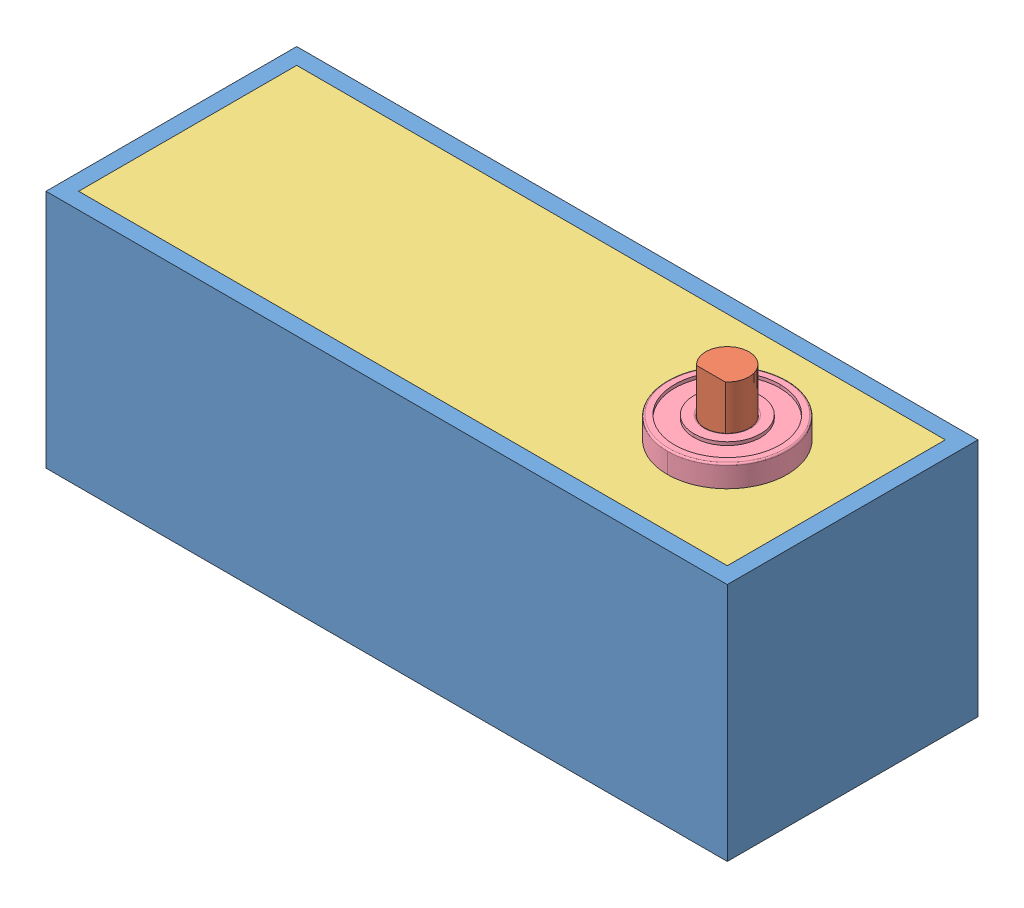
SolidWorks assembly BaseLink, configuration Default. Lengths in mm.
Overall size (125 56 46).
5 component instances, 4 part files, 3 mates.
Components (placement in the parent):
- Motor1WithCase-1: Motor1WithCase [Default] at origin size (125 56 46)
  - ArmBase-1: ArmBase [Default] at origin size (125 44 46)
  - WormGearMotor-2: WormGearMotor [Default] at (-57.7 19.5 0) x (0 0 -1) z (0 -1 0) size (40 117.2 52)
  - ArmBaseCover-2: ArmBaseCover [Default] at (0 44 0) x (-1 0 0) z (0 0 1) size (119 4.5 40)
- SB608ZZ-1: SB608ZZ [Default] at (39.5 48 0) x (0 -1 0) z (0 0 1) size (7 22 22)
Mates (geometry in assembly coordinates):
- Concentric1: concentric anti-aligned: cylinder of Motor1WithCase-1/WormGearMotor-2 through (39.5 36 0) axis (0 1 0) radius 4; cylinder of SB608ZZ-1 through (39.5 41.3 0) axis (0 -1 0) radius 4
- Coincident1: coincident anti-aligned: plane of Motor1WithCase-1/WormGearMotor-2 through (39.5 41 0) normal (0 1 0); plane of SB608ZZ-1 through (49.15 41 0) normal (0 -1 0)
- Coincident3: coordinate: point of Motor1WithCase-1
